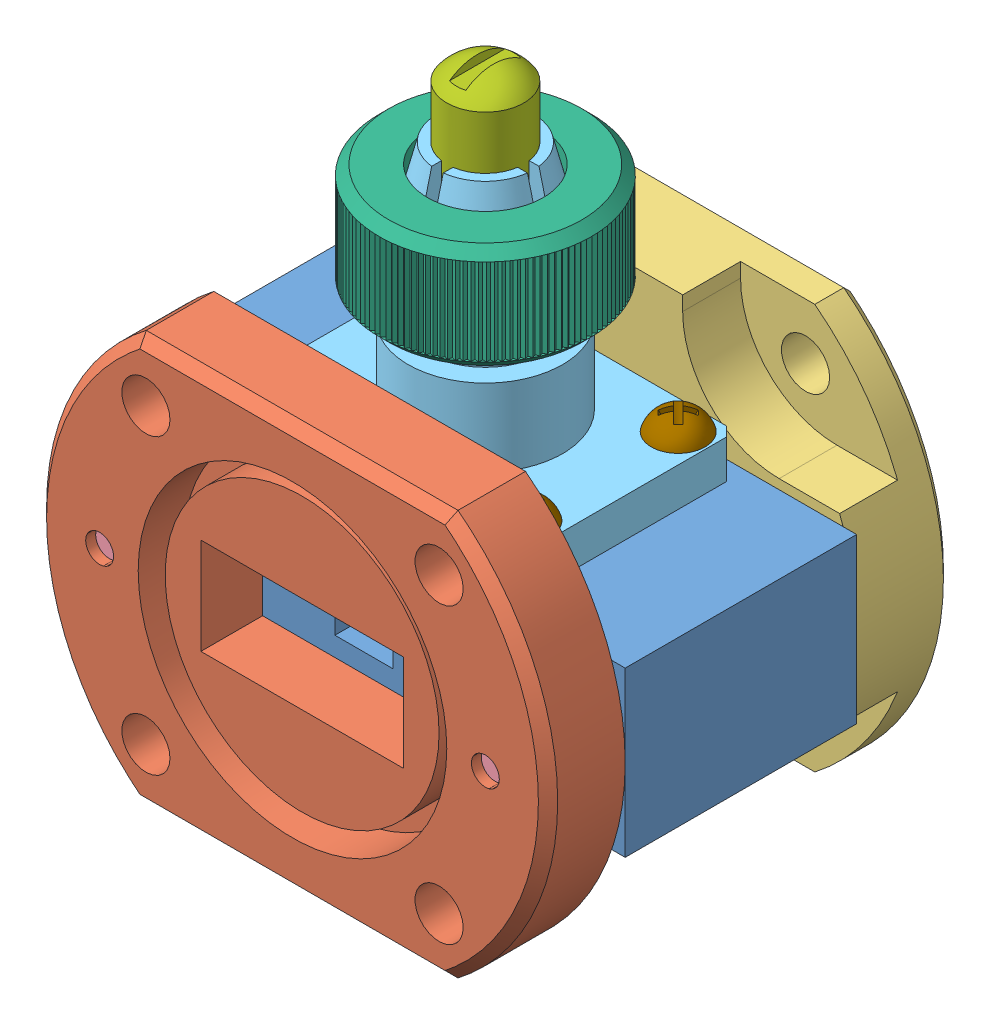
SolidWorks assembly sborka_rezonator, configuration По умолчанию. Lengths in mm.
Overall size (53 64.93 42).
13 component instances, 9 part files, 22 mates.
Components (placement in the parent):
- Корпус-2: Корпус [По умолчанию] at origin size (53 21 25.2)
- Фланец 1-1: Фланец 1 [По умолчанию] at (0 -8.5 12) size (53 42 8)
- Фланец 2-1: Фланец 2 [По умолчанию] at (0 -8.5 -12) x (1 0 0) z (0 0 -1) size (53 42 10)
- Винт М3.5x38 ГОСТ 1491-72-1: Винт М3.5x38 ГОСТ 1491-72 [По умолчанию] at (-20 -8.5 -19) x (-1 0 0) z (0 0 -1) size (6 6 40.4)
- Винт М3.5x38 ГОСТ 1491-72-2: Винт М3.5x38 ГОСТ 1491-72 [По умолчанию] at (20 -8.5 -19) x (-1 0 0) z (0 0 -1) size (6 6 40.4)
- Держатель цанговый-2: Держатель цанговый [По умолчанию] at (7.5 4 0) x (-1 0 0) z (0 -1 0) size (30 22 28)
- Гайка-1: Гайка [По умолчанию] at (0 15 0) x (0.423409 0 -0.905939) z (0.905939 0 0.423409) size (22 11 22)
- Плунжер-5: Плунжер [По умолчанию] at (0 -8.5 0) size (8 43.93 8)
- Крышка-2: Крышка [По умолчанию] at (0 -17 0) x (1 0 0) z (0 1 0) size (22 22 3)
- ГОСТ 17473-80-1: ГОСТ 17473-80 [Винт A2.M3x14 ГОСТ 17473-80] at (12 6.1 -8) x (-0.707107 0 -0.707107) z (0 1 0) size (5.57 5.57 16.06)
- ГОСТ 17473-80-2: ГОСТ 17473-80 [Винт A2.M3x14 ГОСТ 17473-80] at (-12 6.1 -8) x (-0.707107 0 -0.707107) z (0 1 0) size (5.57 5.57 16.06)
- ГОСТ 17473-80-3: ГОСТ 17473-80 [Винт A2.M3x14 ГОСТ 17473-80] at (12 6.1 8) x (-0.707107 0 -0.707107) z (0 1 0) size (5.57 5.57 16.06)
- ГОСТ 17473-80-4: ГОСТ 17473-80 [Винт A2.M3x14 ГОСТ 17473-80] at (-12 6.1 8) x (-0.707107 0 -0.707107) z (0 1 0) size (5.57 5.57 16.06)
Mates (geometry in assembly coordinates):
- Концентричный1: concentric aligned: cylinder of Корпус-2 through (-20 -8.5 -12) axis (0 0 1) radius 1.75; cylinder of Фланец 1-1 through (-20 -8.5 20) axis (0 0 1) radius 1.45
- Концентричный2: concentric aligned: cylinder of Корпус-2 through (20 -8.5 -12) axis (0 0 1) radius 1.75; cylinder of Фланец 1-1 through (20 -8.5 20) axis (0 0 1) radius 1.45
- Совпадение1: coincident anti-aligned: plane of Корпус-2 through (0 0 12) normal (0 0 1); plane of Фланец 1-1 through (0 -8.5 12) normal (0 0 -1)
- Концентричный3: concentric anti-aligned: cylinder of Корпус-2 through (-20 -8.5 -12) axis (0 0 1) radius 1.75; cylinder of Фланец 2-1 through (-20 -8.5 -12) axis (0 0 -1) radius 1.75
- Концентричный4: concentric anti-aligned: cylinder of Корпус-2 through (20 -8.5 -12) axis (0 0 1) radius 1.75; cylinder of Фланец 2-1 through (20 -8.5 -12) axis (0 0 -1) radius 1.75
- Совпадение2: coincident anti-aligned: plane of Корпус-2 through (0 0 -12) normal (0 0 -1); plane of Фланец 2-1 through (0 -8.5 -12) normal (0 0 1)
- Концентричный5: concentric aligned: cylinder of Фланец 2-1 through (-20 -8.5 -12) axis (0 0 -1) radius 1.75; cylinder of Винт М3.5x38 ГОСТ 1491-72-1 through (-20 -8.5 19) axis (0 0 -1) radius 1.75
- Совпадение3: coincident anti-aligned: plane of Фланец 2-1 through (-20 -8.5 -19) normal (0 0 -1); plane of Винт М3.5x38 ГОСТ 1491-72-1 through (-20 -8.5 -19) normal (0 0 1)
- Угол1: planar angle = 1.570796 rad aligned: plane of Винт М3.5x38 ГОСТ 1491-72-1 through (-19.4 29.5 -20.8) normal (-1 0 0); plane of Фланец 2-1 through (-10.5 -3.5 -12) normal (0 -1 0)
- Концентричный6: concentric aligned: cylinder of Корпус-2 through (0 4 0) axis (0 -1 0) radius 7; cylinder of Держатель цанговый-2 through (0 4 0) axis (0 -1 0) radius 7
- Совпадение5: coincident anti-aligned: plane of Корпус-2 through (0 4 0) normal (0 1 0); plane of Держатель цанговый-2 through (0 4 0) normal (0 -1 0)
- Концентричный7: concentric aligned: cylinder of Корпус-2 through (12 0 -8) axis (0 1 0) radius 1.25; cylinder of Держатель цанговый-2 through (12 0 -8) axis (0 1 0) radius 1.5
- Концентричный8: concentric aligned: cylinder of Держатель цанговый-2 through (0 23.3 0) axis (0 -1 0) radius 7; cylinder of Гайка-1 through (0 41.4571 0) axis (0 -1 0) radius 6.172
- Совпадение6: coincident aligned: plane of Держатель цанговый-2 through (0 15 0) normal (0 -1 0); plane of Гайка-1 through (-5.4356 15 -2.5405) normal (0 -1 0)
- Концентричный9: concentric aligned: cylinder of Держатель цанговый-2 through (0 -0.7279 0) axis (0 1 0) radius 3.4455; cylinder of Плунжер-5 through (0 33.5 0) axis (0 1 0) radius 4
- Совпадение9: coincident aligned: plane of Гайка-1 through (-5.4356 15 -2.5405) normal (0 -1 0); plane of Плунжер-5 through (2 15 0) normal (0 -1 0)
- Параллельность2: parallel aligned: plane of Держатель цанговый-2 through (15 0 11) normal (1 0 0); plane of Плунжер-5 through (-0.85 44.5 -4) normal (1 0 0)
- Концентричный10: concentric anti-aligned: cylinder of Корпус-2 through (0 -48.1127 0) axis (0 1 0) radius 11; cylinder of Крышка-2 through (0 -14 0) axis (0 -1 0) radius 11
- Совпадение11: coincident aligned: plane of Корпус-2 through (26.5 -17 -12) normal (0 -1 0); plane of Крышка-2 through (0 -17 0) normal (0 -1 0)
- Концентричный11: concentric aligned: cylinder of Держатель цанговый-2 through (12 0 -8) axis (0 1 0) radius 1.5; cylinder of ГОСТ 17473-80-1 through (12 6.1 -8) axis (0 1 0) radius 1.5
- Совпадение12: coincident anti-aligned: plane of Держатель цанговый-2 through (7.5 4 0) normal (0 1 0); plane of ГОСТ 17473-80-1 through (10.029 4 -6.029) normal (0 -1 0)
- Угол2: planar angle = 0.785398 rad aligned: plane of ГОСТ 17473-80-1 through (11.7575 3.1 -8.2425) normal (0.707107 0 0.707107); plane of Держатель цанговый-2 through (15 0 11) normal (1 0 0)
